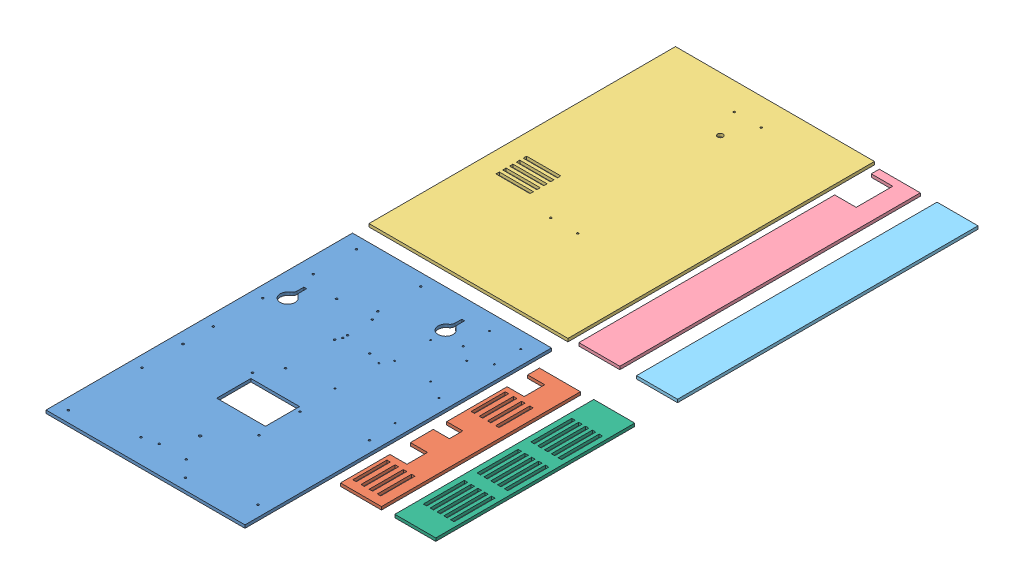
SolidWorks assembly laser, configuration Default. Lengths in mm.
Overall size (569.93 5.64 1170.65).
6 component instances, 6 part files, 12 mates.
Components (placement in the parent):
- acrylic back-1: acrylic back [Default] at (615.7679 1.7487 602.4787) size (370 5.64 570)
- Acrylic bottom-1: Acrylic bottom [Default] at (243.2929 1.7487 34.4878) x (0 0 1) z (-1 0 0) size (370 5.64 76.2)
- Acrylic cover-1: Acrylic cover [Default] at (-35.9949 4.5681 -794.769) x (-1 0 0) z (0 1 0) size (370 570 5.64)
- Acrylic left side-1: Acrylic left side [Default] at (238.9895 1.7487 -601.861) x (0 0 1) z (-1 0 0) size (558.72 5.64 76.2)
- Acrylic right side-1: Acrylic right side [Default] at (345.7608 1.7487 -602.4108) x (0 0 1) z (-1 0 0) size (558.72 5.64 76.2)
- Acrylic top-1: Acrylic top [Default] at (344.3222 1.7487 34.4878) x (0 0 1) z (-1 0 0) size (370 5.64 76.2)
Mates (geometry in assembly coordinates):
- Coincident1: coincident aligned: plane of acrylic back-1 through (615.7679 1.7487 602.4787) normal (0 -1 0); plane of Acrylic cover-1 through (-220.9949 1.7487 -224.769) normal (0 -1 0)
- Coincident2: coincident aligned: plane of acrylic back-1 through (615.7679 1.7487 602.4787) normal (0 -1 0); plane of Acrylic left side-1 through (238.9895 1.7487 -601.861) normal (0 -1 0)
- Coincident3: coincident aligned: plane of acrylic back-1 through (615.7679 1.7487 602.4787) normal (0 -1 0); plane of Acrylic bottom-1 through (243.2929 1.7487 34.4878) normal (0 -1 0)
- Coincident4: coincident aligned: plane of acrylic back-1 through (615.7679 1.7487 602.4787) normal (0 -1 0); plane of Acrylic right side-1 through (345.7608 1.7487 -602.4108) normal (0 -1 0)
- Coincident6: coincident aligned: plane of acrylic back-1 through (615.7679 1.7487 602.4787) normal (0 -1 0); plane of Acrylic top-1 through (344.3222 1.7487 37.4526) normal (0 -1 0)
- Parallel1: parallel anti-aligned: plane of Acrylic cover-1 through (149.0051 1.7487 -224.769) normal (1 0 0); plane of Acrylic left side-1 through (165.9645 7.3875 -786.861) normal (-1 0 0)
- Parallel2: parallel anti-aligned: plane of Acrylic left side-1 through (242.1645 7.3875 -786.861) normal (1 0 0); plane of Acrylic right side-1 through (272.7358 7.3875 -787.4108) normal (-1 0 0)
- Coincident9: coincident aligned: plane of acrylic back-1 through (-220.9949 7.3875 369.5353) normal (-1 0 0); plane of Acrylic cover-1 through (-220.9949 1.7487 -224.769) normal (-1 0 0)
- Parallel3: parallel anti-aligned: plane of acrylic back-1 through (-220.9949 7.3875 -194.1147) normal (0 0 -1); plane of Acrylic cover-1 through (-35.9949 4.5681 -224.769) normal (0 0 1)
- Parallel4: parallel anti-aligned: plane of acrylic back-1 through (149.0051 7.3875 369.5353) normal (1 0 0); plane of Acrylic bottom-1 through (170.2679 7.3875 -150.5122) normal (-1 0 0)
- Parallel5: parallel anti-aligned: plane of Acrylic bottom-1 through (246.4679 7.3875 -150.5122) normal (1 0 0); plane of Acrylic top-1 through (271.2972 7.3875 -150.5122) normal (-1 0 0)
- Coincident13: coincident aligned: plane of Acrylic bottom-1 through (236.4679 7.3875 -150.5122) normal (0 0 -1); plane of Acrylic top-1 through (337.4972 7.3875 -150.5122) normal (0 0 -1)
